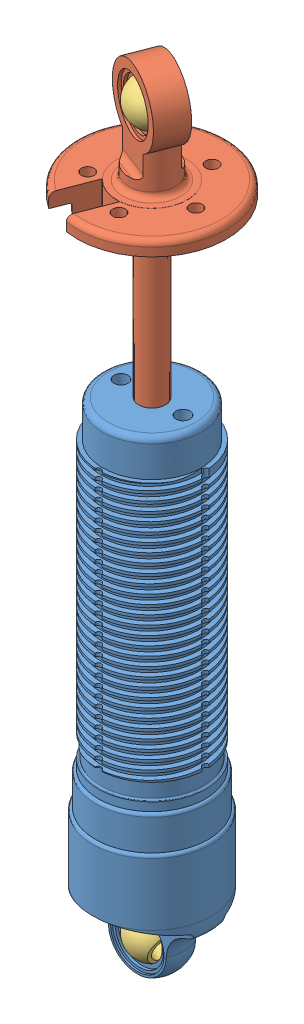
SolidWorks assembly Afco Shock, configuration Default. Lengths in mm.
Overall size (68.37 280.52 68.12).
4 component instances, 3 part files, 7 mates.
Components (placement in the parent):
- Afco Body-1: Afco Body [Default] at (0 164.5 0) x (1 0 0) z (0 -1 0) size (42 43.69 176)
- Stopper-2: Stopper [Default] at (0 164.3512 0) x (0.932888 0 0.360167) z (-0.360167 0 0.932888) size (53 104.25 52.55)
- Spherical Bearing-1: Spherical Bearing [Default] x (-0.938513 0.295839 -0.177969) z (-0.039631 0.419763 0.906768) size (12 15.88 15.88)
- Spherical Bearing-2: Spherical Bearing [Default] at (0 255.8512 0) size (12 15.88 15.88)
Mates (geometry in assembly coordinates):
- Coincident3: coincident: point of Spherical Bearing-1; point of assembly
- Coincident2: coincident: point of Afco Body-1; point of assembly
- Coincident4: coincident: point of Stopper-2; point of Spherical Bearing-2
- Concentric1: concentric anti-aligned: cylinder of Afco Body-1 through (0 73.5 0) axis (0 1 0) radius 4.75; cylinder of Stopper-2 through (0 222.3512 0) axis (0 -1 0) radius 4.75
- LimitDistance1: limit distance = 0.1488 mm anti-aligned: plane of Stopper-2 through (0 164.3512 0) normal (0 -1 0); plane of Afco Body-1 through (0 164.5 0) normal (0 1 0)
- Coincident5: coincident aligned: plane of Afco Body-1; plane of assembly through (0 0 0) normal (1 0 0)
- Coincident6: coincident aligned: plane of Afco Body-1 through (0 164.5 0) normal (0 0 1); plane of assembly through (0 0 0) normal (0 0 1)
